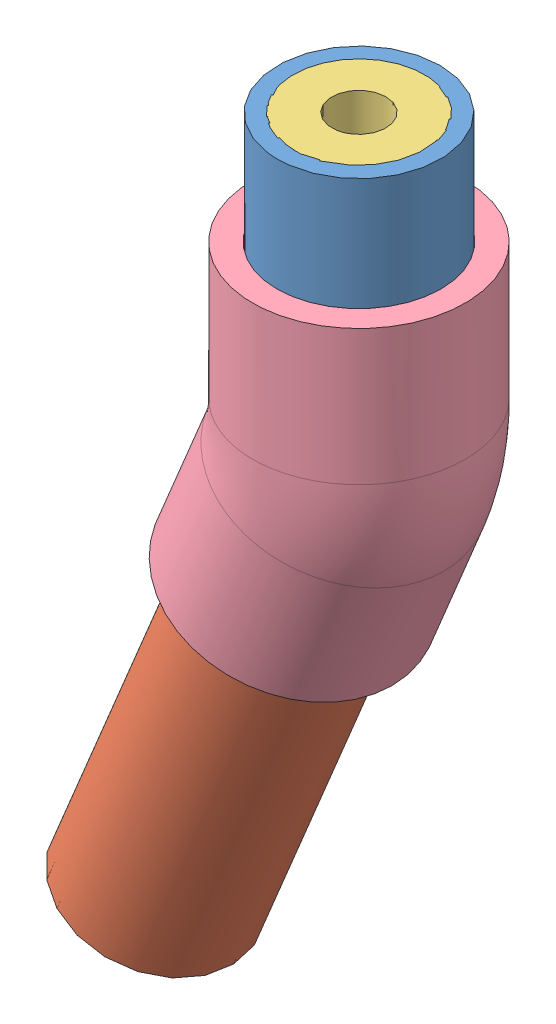
SolidWorks assembly BentRudderTube, configuration Default. Lengths in mm.
Overall size (85.08 167.37 46.84).
7 component instances, 4 part files, 10 mates.
Components (placement in the parent):
- VerticalPVC-1: VerticalPVC [Default] at (-78.74 -37.7825 82.55) size (33.4 50.8 33.4)
- AngledPVC-1: AngledPVC [Default] at (-120.3544 -145.3924 82.55) x (0.563065 -0.233229 0.792819) z (-0.732469 0.303399 0.609457) size (33.4 101.6 33.4)
- UHMW_Bearing-1: UHMW_Bearing [Default] at (-93.1744 -79.7741 82.55) x (0.92154 -0.381714 -0.071118) z (0.065704 -0.027216 0.997468) size (26.92 12.7 26.92)
- UHMW_Bearing-2: UHMW_Bearing [Default] at (-78.74 -19.9073 82.55) size (26.92 12.7 26.92)
- UHMW_Bearing-3: UHMW_Bearing [Default] at (-78.74 0.3175 82.55) x (0.941661 0 -0.336564) z (0.336564 0 0.941661) size (26.92 12.7 26.92)
- 4880K703_STANDARD-WALL WHITE PVC PIPE FITTING-1: 4880K703_STANDARD-WALL WHITE PVC PIPE FITTING [4880K703] at (-78.74 -44.9263 82.55) size (55.36 75.54 43.66)
- UHMW_Bearing-4: UHMW_Bearing [Default] at (-120.3544 -145.3924 82.55) x (0.92388 -0.382683 0) z (0 0 1) size (26.92 12.7 26.92)
Mates (geometry in assembly coordinates):
- Concentric65: concentric anti-aligned: circle of 4880K703_STANDARD-WALL WHITE PVC PIPE FITTING-1; circle of VerticalPVC-1
- Coincident26: coincident anti-aligned: circle of 4880K703_STANDARD-WALL WHITE PVC PIPE FITTING-1; plane of VerticalPVC-1 through (-78.74 -37.7825 82.55) normal (0 -1 0)
- Concentric70: concentric aligned: cylinder of VerticalPVC-1 through (-78.74 13.0175 82.55) axis (0 -1 0) radius 13.3223; cylinder of UHMW_Bearing-2 through (-78.74 -7.2073 82.55) axis (0 -1 0) radius 13.462
- Concentric71: concentric aligned: cylinder of VerticalPVC-1 through (-78.74 13.0175 82.55) axis (0 -1 0) radius 16.7005; cylinder of UHMW_Bearing-3 through (-78.74 13.0175 82.55) axis (0 -1 0) radius 13.462
- Coincident29: coincident aligned: plane of VerticalPVC-1 through (-78.74 13.0175 82.55) normal (0 1 0); plane of UHMW_Bearing-3 through (-78.74 13.0175 82.55) normal (0 1 0)
- Concentric64: concentric anti-aligned: circle of 4880K703_STANDARD-WALL WHITE PVC PIPE FITTING-1; circle of AngledPVC-1
- Coincident25: coincident aligned: circle of 4880K703_STANDARD-WALL WHITE PVC PIPE FITTING-1; plane of AngledPVC-1 through (-81.4738 -51.5262 82.55) normal (0.382683 0.92388 0)
- Concentric72: concentric aligned: circle of AngledPVC-1; circle of UHMW_Bearing-4
- Coincident30: coincident aligned: plane of AngledPVC-1 through (-120.3544 -145.3924 82.55) normal (-0.382683 -0.92388 0); plane of UHMW_Bearing-4 through (-120.3544 -145.3924 82.55) normal (-0.382683 -0.92388 0)
- Concentric73: concentric aligned: cylinder of AngledPVC-1 through (-81.4738 -51.5262 82.55) axis (-0.382683 -0.92388 0) radius 16.7005; cylinder of UHMW_Bearing-1 through (-88.3144 -68.0408 82.55) axis (-0.382683 -0.92388 0) radius 13.462
